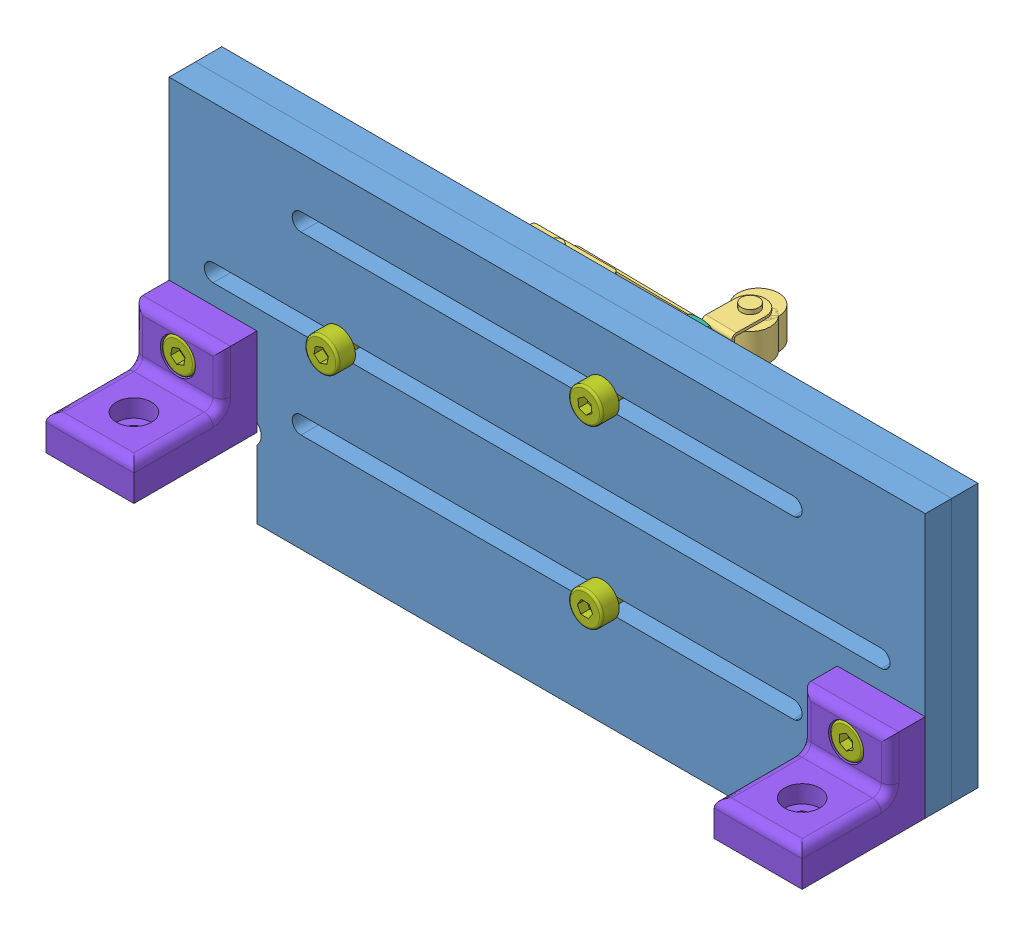
SolidWorks assembly cfc_ouvert, configuration Défaut. Lengths in mm.
Overall size (86 39 42.4).
21 component instances, 8 part files, 44 mates.
Components (placement in the parent):
- cfc-platine-1: cfc-platine [Défaut] at (140.8628 -70 0) x (0 0 1) z (0 -1 0) size (3 86 39)
- Grove microswitch v1.0-1: Grove microswitch v1.0 [Défaut] at (-48.6908 22.25 -3.344) x (-1 0 0) z (0 -1 0) size (41.8 22.4 23.6)
  - PCB grove 20x40-1: PCB grove 20x40 [Défaut] at (-1.988 -1.344 0) size (41.8 1.6 23.6)
  - microswitch 10T85-1: microswitch 10T85 [Défaut] at (9.562 0.256 0) size (22.48 22.4 6.4)
  - Connecteur Grove (coudé CMS)-1: Connecteur Grove (coudé CMS) [Défaut] at (-21.488 0.256 0) x (0 0 -1) z (0 1 0) size (12 10 5)
- entretoise-grove-1: entretoise-grove [Défaut] at (-66.7028 22.25 -2) x (1 0.000242 0) z (0 0 1) size (4 4 2)
- entretoise-grove-2: entretoise-grove [Défaut] at (-36.7028 32.25 -2) size (4 4 2)
- entretoise-grove-3: entretoise-grove [Défaut] at (-36.7028 12.25 -2) size (4 4 2)
- ecrou-h-2: ecrou-h [6007 HU M2] at (-36.7028 32.25 -5.2) x (-0.866025 0.5 0) z (-0.5 -0.866025 0) size (4 1.6 4.62)
- ecrou-h-3: ecrou-h [6007 HU M2] at (-36.7028 12.25 -5.2) x (0.866025 0.5 0) z (-0.5 0.866025 0) size (4 1.6 4.62)
- vis-chc-1: vis-chc [Vis CHC M2x12] at (-36.7028 32.25 6) x (0.144676 -0.989479 0) z (-0.989479 -0.144676 0) size (3.8 14 3.8)
- vis-chc-2: vis-chc [Vis CHC M2x12] at (-36.7028 12.25 6) x (0.999846 -0.017534 0) z (-0.017534 -0.999846 0) size (3.8 14 3.8)
- vis-chc-3: vis-chc [Vis CHC M2x12] at (-66.7028 22.25 6) x (-0.77641 0.630228 0) z (0.630228 0.77641 0) size (3.8 14 3.8)
- vis-chc-5: vis-chc [Vis CHC M2x10] at (-5 16 8) x (0.048861 -0.998806 0) z (-0.998806 -0.048861 0) size (3.8 12 3.8)
- vis-chc-6: vis-chc [Vis CHC M2x10] at (-81 16 8) x (-0.923728 -0.383049 0) z (-0.383049 0.923728 0) size (3.8 12 3.8)
- ecrou-h-6: ecrou-h [6007 HU M2] at (-81 16 -1.6) x (1 0 0) z (0 1 0) size (4 1.6 4.62)
- ecrou-h-8: ecrou-h [6007 HU M2] at (-5 16 -1.6) x (1 0 0) z (0 1 0) size (4 1.6 4.62)
- cfc-platine-2: cfc-platine [Défaut] at (140.8628 -70 3) x (0 0 1) z (0 -1 0) size (3 86 39)
- ecrou-h-4: ecrou-h [6007 HU M2] at (-66.7028 22.25 -5.2) x (1 0 0) z (0 1 0) size (4 1.6 4.62)
- equerre-basse-1: equerre-basse [Défaut] at (-81 9 6) size (10 10 14)
- equerre-basse-2: equerre-basse [Défaut] at (-5 9 6) size (10 10 14)
Mates (geometry in assembly coordinates):
- Coaxiale1: concentric anti-aligned: cylinder of Grove microswitch v1.0-1/PCB grove 20x40-1 through (-36.7028 12.25 -3.6) axis (0 0 1) radius 1.1; cylinder of entretoise-grove-3 through (-36.7028 12.25 0) axis (0 0 -1) radius 1.1
- Coïncidente4: coincident anti-aligned: plane of Grove microswitch v1.0-1/PCB grove 20x40-1 through (-46.7028 22.25 -2) normal (0 0 1); plane of entretoise-grove-3 through (-36.7028 12.25 -2) normal (0 0 -1)
- Coaxiale2: concentric anti-aligned: cylinder of Grove microswitch v1.0-1/PCB grove 20x40-1 through (-66.7028 22.25 -3.6) axis (0 0 1) radius 1.1; cylinder of entretoise-grove-1 through (-66.7028 22.25 0) axis (0 0 -1) radius 1.1
- Coïncidente5: coincident anti-aligned: plane of Grove microswitch v1.0-1/PCB grove 20x40-1 through (-46.7028 22.25 -2) normal (0 0 1); plane of entretoise-grove-1 through (-66.7028 22.25 -2) normal (0 0 -1)
- Coaxiale3: concentric anti-aligned: cylinder of Grove microswitch v1.0-1/PCB grove 20x40-1 through (-36.7028 32.25 -3.6) axis (0 0 1) radius 1.1; cylinder of entretoise-grove-2 through (-36.7028 32.25 0) axis (0 0 -1) radius 1.1
- Coïncidente6: coincident anti-aligned: plane of Grove microswitch v1.0-1/PCB grove 20x40-1 through (-46.7028 22.25 -2) normal (0 0 1); plane of entretoise-grove-2 through (-36.7028 32.25 -2) normal (0 0 -1)
- Coïncidente7: coincident anti-aligned: plane of cfc-platine-1 through (-8.8686 8.8686 0) normal (0 0 -1); plane of entretoise-grove-1 through (-66.7028 22.25 0) normal (0 0 1)
- Parallèle4: parallel aligned: plane of cfc-platine-1 through (-86 39 3) normal (-1 0 0); plane of Grove microswitch v1.0-1/PCB grove 20x40-1 through (-66.7028 22.25 -3.6) normal (-1 0 0)
- Parallèle3: parallel aligned: plane of cfc-platine-1 through (-10 0 3) normal (0 -1 0); plane of Grove microswitch v1.0-1/PCB grove 20x40-1 through (-46.7028 12.25 -3.6) normal (0 -1 0)
- Coaxiale4: concentric aligned: cylinder of Grove microswitch v1.0-1/PCB grove 20x40-1 through (-36.7028 32.25 -3.6) axis (0 0 1) radius 1.1; cylinder of vis-chc-1 through (-36.7028 32.25 -6) axis (0 0 1) radius 1
- Coaxiale5: concentric aligned: cylinder of Grove microswitch v1.0-1/PCB grove 20x40-1 through (-66.7028 22.25 -3.6) axis (0 0 1) radius 1.1; cylinder of vis-chc-3 through (-66.7028 22.25 -6) axis (0 0 1) radius 1
- Coaxiale6: concentric aligned: cylinder of Grove microswitch v1.0-1/PCB grove 20x40-1 through (-36.7028 12.25 -3.6) axis (0 0 1) radius 1.1; cylinder of vis-chc-2 through (-36.7028 12.25 -6) axis (0 0 1) radius 1
- Coaxiale7: concentric anti-aligned: cylinder of ecrou-h-2 through (-36.7028 32.25 -3.6) axis (0 0 -1) radius 0.7835; cylinder of vis-chc-1 through (-36.7028 32.25 -6) axis (0 0 1) radius 1
- Coaxiale8: concentric anti-aligned: cylinder of ecrou-h-3 through (-36.7028 12.25 -3.6) axis (0 0 -1) radius 0.7835; cylinder of vis-chc-2 through (-36.7028 12.25 -6) axis (0 0 1) radius 1
- Parallèle5: parallel aligned: plane of cfc-platine-1 through (0 39 3) normal (0 1 0); plane of ecrou-h-2 through (-37.8575 34.25 -3.6) normal (0 1 0)
- Parallèle7: parallel aligned: plane of ecrou-h-2 through (-37.8575 34.25 -3.6) normal (0 1 0); plane of ecrou-h-3 through (-37.8575 14.25 -3.6) normal (0 1 0)
- Tangent1: tangent anti-aligned: plane of cfc-platine-1 through (-15 31.25 3) normal (0 1 0); cylinder of vis-chc-1 through (-36.7028 32.25 -6) axis (0 0 1) radius 1
- Coïncidente17: coincident anti-aligned: plane of cfc-platine-1 through (-8.8686 8.8686 3) normal (0 0 1); plane of cfc-platine-2 through (-8.8686 8.8686 3) normal (0 0 -1)
- Coïncidente19: coincident aligned: plane of cfc-platine-1 through (-86 39 3) normal (-1 0 0); plane of cfc-platine-2 through (-86 39 6) normal (-1 0 0)
- Coïncidente20: coincident aligned: plane of cfc-platine-1 through (0 39 3) normal (0 1 0); plane of cfc-platine-2 through (0 39 6) normal (0 1 0)
- Coïncidente21: coincident anti-aligned: plane of vis-chc-3 through (-66.7028 22.25 6) normal (0 0 -1); plane of cfc-platine-2 through (-8.8686 8.8686 6) normal (0 0 1)
- Coaxiale9: concentric anti-aligned: cylinder of vis-chc-3 through (-66.7028 22.25 -6) axis (0 0 1) radius 1; cylinder of ecrou-h-4 through (-66.7028 22.25 -3.6) axis (0 0 -1) radius 0.7835
- Parallèle8: parallel aligned: plane of Grove microswitch v1.0-1/microswitch 10T85-1 through (-64.7028 19.25 -13.9) normal (-1 0 0); plane of ecrou-h-4 through (-68.7028 21.0953 -3.6) normal (-1 0 0)
- Coïncidente23: coincident anti-aligned: plane of Grove microswitch v1.0-1/PCB grove 20x40-1 through (-46.7028 22.25 -3.6) normal (0 0 -1); plane of ecrou-h-4 through (-64.7028 21.0953 -3.6) normal (0 0 1)
- Coïncidente24: coincident anti-aligned: plane of vis-chc-1 through (-36.7028 32.25 6) normal (0 0 -1); plane of cfc-platine-2 through (-8.8686 8.8686 6) normal (0 0 1)
- Coïncidente25: coincident anti-aligned: plane of Grove microswitch v1.0-1/PCB grove 20x40-1 through (-46.7028 22.25 -3.6) normal (0 0 -1); plane of ecrou-h-2 through (-37.8575 34.25 -3.6) normal (0 0 1)
- Parallèle9: parallel aligned: plane of Grove microswitch v1.0-1/PCB grove 20x40-1 through (-46.7028 32.25 -3.6) normal (0 1 0); plane of ecrou-h-2 through (-37.8575 34.25 -3.6) normal (0 1 0)
- Coïncidente28: coincident anti-aligned: plane of Grove microswitch v1.0-1/PCB grove 20x40-1 through (-46.7028 22.25 -3.6) normal (0 0 -1); plane of ecrou-h-3 through (-34.3934 12.25 -3.6) normal (0 0 1)
- Coïncidente29: coincident anti-aligned: plane of cfc-platine-2 through (-8.8686 8.8686 6) normal (0 0 1); plane of equerre-1 through (-81 9 6) normal (0 0 -1)
- Coïncidente30: coincident aligned: plane of cfc-platine-2 through (-86 39 6) normal (-1 0 0); plane of equerre-1 through (-86 19 10) normal (-1 0 0)
- Coïncidente31: coincident aligned: plane of cfc-platine-2 through (-78.726 9 6) normal (0 -1 0); plane of equerre-1 through (-86 9 10) normal (0 -1 0)
- Coaxiale10: concentric aligned: cylinder of equerre-1 through (-81 16 6) axis (0 0 1) radius 1.1; cylinder of vis-chc-6 through (-81 16 -2) axis (0 0 1) radius 1
- Coaxiale13: concentric anti-aligned: cylinder of cfc-platine-2 through (-5 16 6) axis (0 0 -1) radius 1; cylinder of vis-chc-5 through (-5 16 -2) axis (0 0 1) radius 1
- Coïncidente35: coincident anti-aligned: plane of equerre-1 through (-81 16 8) normal (0 0 1); plane of vis-chc-6 through (-81 16 8) normal (0 0 -1)
- Coïncidente36: coincident aligned: plane of equerre-1 through (-86 9 10) normal (0 -1 0); plane of equerre-2 through (-10 9 10) normal (0 -1 0)
- Coaxiale14: concentric anti-aligned: cylinder of cfc-platine-2 through (-5 16 6) axis (0 0 -1) radius 1; cylinder of equerre-2 through (-5 16 6) axis (0 0 1) radius 1.1
- Coaxiale17: concentric anti-aligned: cylinder of vis-chc-6 through (-81 16 -2) axis (0 0 1) radius 1; cylinder of ecrou-h-6 through (-81 16 0) axis (0 0 -1) radius 0.7835
- Coaxiale19: concentric anti-aligned: cylinder of vis-chc-5 through (-5 16 -2) axis (0 0 1) radius 1; cylinder of ecrou-h-8 through (-5 16 0) axis (0 0 -1) radius 0.7835
- Coïncidente38: coincident anti-aligned: plane of cfc-platine-1 through (-8.8686 8.8686 0) normal (0 0 -1); plane of ecrou-h-8 through (-3 14.8453 0) normal (0 0 1)
- Parallèle10: parallel aligned: plane of cfc-platine-1 through (0 9 3) normal (1 0 0); plane of ecrou-h-8 through (-3 17.1547 0) normal (1 0 0)
- Coïncidente44: coincident anti-aligned: plane of cfc-platine-1 through (-8.8686 8.8686 0) normal (0 0 -1); plane of ecrou-h-6 through (-79 14.8453 0) normal (0 0 1)
- Parallèle13: parallel aligned: plane of cfc-platine-1 through (-86 39 3) normal (-1 0 0); plane of ecrou-h-6 through (-83 14.8453 0) normal (-1 0 0)
- Coïncidente45: coincident anti-aligned: plane of cfc-platine-2 through (-8.8686 8.8686 6) normal (0 0 1); plane of equerre-2 through (-5 9 6) normal (0 0 -1)
- Coïncidente46: coincident anti-aligned: plane of vis-chc-5 through (-5 16 8) normal (0 0 -1); plane of equerre-2 through (-5 16 8) normal (0 0 1)
